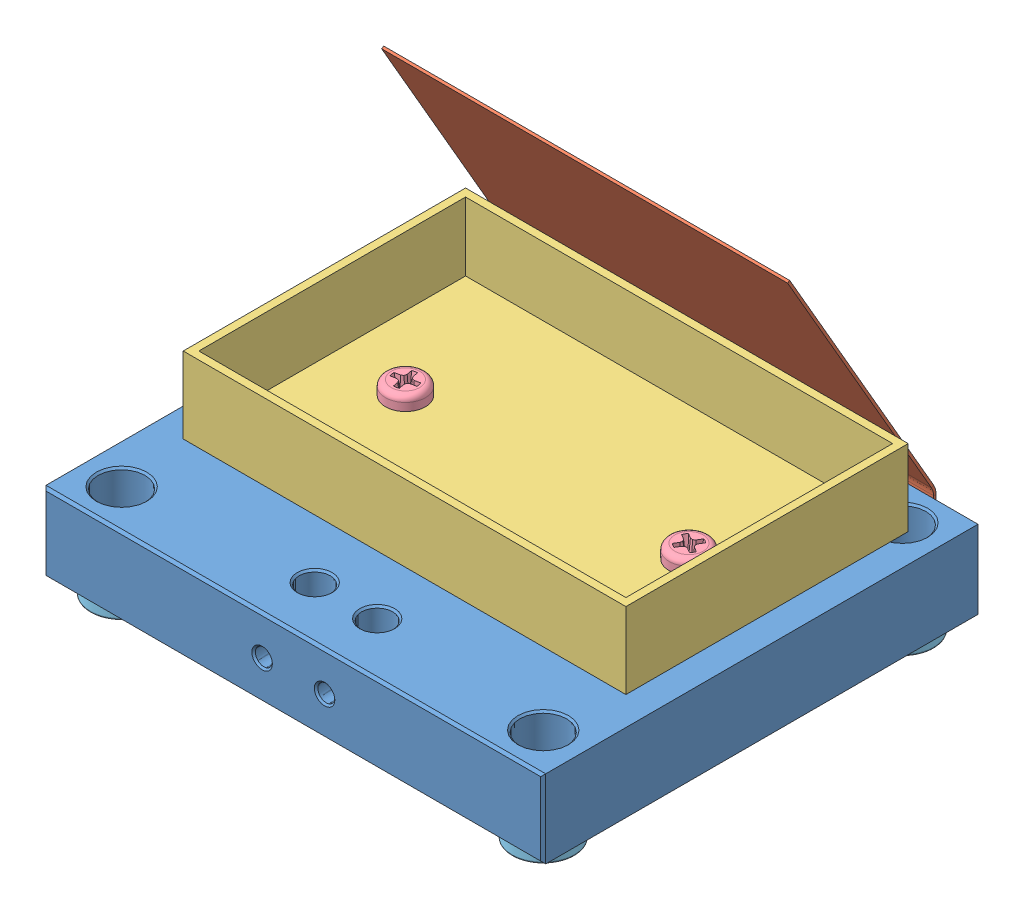
SolidWorks assembly Base_assy, configuration Default. Lengths in mm.
Overall size (101.6 71.58 93.29).
11 component instances, 6 part files, 38 mates.
Components (placement in the parent):
- Base-1: Base [Default] at (101.6 22.2369 0) x (1 0 0) z (0 -1 0) size (101.6 88.9 15.88)
- Plate-1: Plate [Default] at (92.075 22.2369 -0.508) x (0 1 0) z (1 0 0) size (68.4 30.2 82.55)
- 1155_battery_holder-1: 1155_battery_holder [Default] at (95.8 22.2369 8.89) x (0 0 1) z (-1 0 0) size (57.4 15.49 90)
- 8_32_500_nylon_93135A353-1: 8_32_500_nylon_93135A353 [93135A353] at (79.925 23.8244 37.592) x (0.857399 0 0.514652) z (0 1 0) size (8.13 8.13 15.77)
- 8_32_500_nylon_93135A353-2: 8_32_500_nylon_93135A353 [93135A353] at (22.2797 23.8244 37.592) x (0.982082 0 -0.188455) z (0 1 0) size (8.13 8.13 15.77)
- 9309K62_Tight-Grip Push-In Bumpers-1: 9309K62_Tight-Grip Push-In Bumpers [9309K62] at (93.6625 6.3619 7.9375) x (-1 0 0) z (0 0 1) size (12.7 12.7 12.7)
- 9309K62_Tight-Grip Push-In Bumpers-2: 9309K62_Tight-Grip Push-In Bumpers [9309K62] at (93.6625 6.3619 80.9625) x (-1 0 0) z (0 0 1) size (12.7 12.7 12.7)
- 9309K62_Tight-Grip Push-In Bumpers-3: 9309K62_Tight-Grip Push-In Bumpers [9309K62] at (7.9375 6.3619 80.9625) x (-1 0 0) z (0 0 1) size (12.7 12.7 12.7)
- 9309K62_Tight-Grip Push-In Bumpers-4: 9309K62_Tight-Grip Push-In Bumpers [9309K62] at (7.9375 6.3619 7.9375) x (-1 0 0) z (0 0 1) size (12.7 12.7 12.7)
- 90081A291_Zinc-Plated Steel Screw Nails-1: 90081A291_Zinc-Plated Steel Screw Nails [90081A291] at (76.2 14.2994 3.8989) x (0 0 1) z (-1 0 0) size (16.59 10.36 10.36)
- 90081A291_Zinc-Plated Steel Screw Nails-2: 90081A291_Zinc-Plated Steel Screw Nails [90081A291] at (25.4 14.2994 3.8989) x (0 0 1) z (-0.987351 -0.158553 0) size (16.59 10.36 10.36)
Mates (geometry in assembly coordinates):
- Concentric41: concentric: cylinder of ? through (17.4625 25.6067 6.35) axis (0 -1 0) radius 4.064; cylinder of Base-1 through (17.4625 9.5369 6.35) axis (0 -1 0) radius 1.7272
- Concentric44: concentric: cylinder of Base-1 through (84.1375 9.5369 6.35) axis (0 -1 0) radius 1.7272; cylinder of ? through (84.1375 27.5709 6.35) axis (0 -1 0) radius 4.064
- Coincident59: coincident: plane of ? through (84.1375 24.7769 6.35) normal (0 1 0); plane of ? through (84.1375 24.7769 6.35) normal (0 -1 0)
- Coincident61: coincident: plane of ? through (17.4625 24.7769 6.35) normal (0 -1 0); plane of ? through (17.4625 24.7769 6.35) normal (0 1 0)
- Width2: width anti-aligned: plane of Plate-1 through (92.075 22.2369 0) normal (1 0 0); plane of Base-1 through (9.525 22.2369 0) normal (-1 0 0); plane of Plate-1 through (0 6.3619 0) normal (-1 0 0); plane of Base-1 through (101.6 6.3619 0) normal (1 0 0)
- Distance2: distance = 8.89 mm aligned: plane of Base-1 through (101.6 6.3619 0) normal (0 0 -1); plane of 1155_battery_holder-1 through (95.8 23.8244 8.89) normal (0 0 -1)
- Width3: width anti-aligned: plane of Base-1 through (0 6.3619 0) normal (-1 0 0); plane of 1155_battery_holder-1 through (101.6 6.3619 0) normal (1 0 0); plane of Base-1 through (95.8 23.8244 8.89) normal (1 0 0); plane of 1155_battery_holder-1 through (5.8 23.8244 8.89) normal (-1 0 0)
- Coincident65: coincident anti-aligned: plane of Base-1 through (101.6 22.2369 0) normal (0 1 0); plane of ? through (22.2797 22.2369 36.6395) normal (0 -1 0)
- Coincident66: coincident anti-aligned: plane of 1155_battery_holder-1 through (95.8 23.8244 8.89) normal (0 1 0); plane of 8_32_500_nylon_93135A353-1 through (79.925 23.8244 37.592) normal (0 -1 0)
- Concentric55: concentric anti-aligned: cylinder of 1155_battery_holder-1 through (79.925 23.8244 37.592) axis (0 1 0) radius 2.2479; cylinder of 8_32_500_nylon_93135A353-1 through (79.925 26.6184 37.592) axis (0 -1 0) radius 4.064
- Coincident67: coincident anti-aligned: plane of 1155_battery_holder-1 through (95.8 23.8244 8.89) normal (0 1 0); plane of 8_32_500_nylon_93135A353-2 through (22.2797 23.8244 37.592) normal (0 -1 0)
- Concentric56: concentric anti-aligned: cylinder of 1155_battery_holder-1 through (22.2797 23.8244 37.592) axis (0 1 0) radius 2.2479; cylinder of 8_32_500_nylon_93135A353-2 through (22.2797 26.6184 37.592) axis (0 -1 0) radius 4.064
- Concentric57: concentric: cylinder of ? through (17.4625 27.5709 6.35) axis (0 -1 0) radius 4.064; circle of ?
- Concentric58: concentric: cylinder of ? through (17.4625 27.5709 6.35) axis (0 -1 0) radius 4.064; circle of ?
- Coincident69: coincident: plane of ? through (17.4625 23.7609 6.35) normal (0 1 0); plane of ? through (17.4625 23.7609 6.35) normal (0 -1 0)
- Concentric59: concentric: cylinder of ? through (84.1375 27.5709 6.35) axis (0 -1 0) radius 4.064; circle of ?
- Concentric60: concentric: cylinder of ? through (84.1375 27.5709 6.35) axis (0 -1 0) radius 4.064; circle of ?
- Coincident71: coincident: plane of ? through (84.1375 23.7609 6.35) normal (0 1 0); plane of ? through (84.1375 23.7609 6.35) normal (0 -1 0)
- Coincident72: coincident anti-aligned: plane of Base-1 through (101.6 22.2369 0) normal (0 1 0); plane of 1155_battery_holder-1 through (95.8 22.2369 8.89) normal (0 -1 0)
- Coincident73: coincident anti-aligned: plane of Base-1 through (101.6 6.3619 0) normal (0 0 -1); plane of Plate-1 through (92.075 22.2369 0) normal (0 0 1)
- Concentric61: concentric aligned: cylinder of Base-1 through (76.2 14.2994 0) axis (0 0 -1) radius 2.4892; cylinder of Plate-1 through (76.2 14.2994 -0.508) axis (0 0 -1) radius 3.175
- Concentric62: concentric anti-aligned: cylinder of Base-1 through (76.2 14.2994 0) axis (0 0 -1) radius 2.4892; cylinder of ? through (76.2 15.8869 -3.302) axis (0 0 1) radius 4.064
- Coincident75: coincident anti-aligned: plane of Base-1 through (101.6 6.3619 0) normal (0 -1 0); plane of 9309K62_Tight-Grip Push-In Bumpers-1 through (87.3125 6.3619 7.9375) normal (0 1 0)
- Concentric65: concentric aligned: cylinder of Base-1 through (93.6625 22.2369 7.9375) axis (0 -1 0) radius 3.175; cylinder of 9309K62_Tight-Grip Push-In Bumpers-1 through (93.6625 3.1869 7.9375) axis (0 -1 0) radius 3.175
- Parallel4: parallel aligned: plane of 9309K62_Tight-Grip Push-In Bumpers-1 through (93.6625 6.3619 7.9375) normal (0 0 1)
- Coincident77: coincident anti-aligned: plane of Base-1 through (101.6 6.3619 0) normal (0 -1 0); plane of 9309K62_Tight-Grip Push-In Bumpers-2 through (87.3125 6.3619 80.9625) normal (0 1 0)
- Parallel5: parallel aligned: plane of 9309K62_Tight-Grip Push-In Bumpers-2 through (93.6625 6.3619 80.9625) normal (0 0 1)
- Concentric66: concentric anti-aligned: cylinder of Base-1 through (93.6625 22.2369 80.9625) axis (0 1 0) radius 4.7625; cylinder of 9309K62_Tight-Grip Push-In Bumpers-2 through (93.6625 3.1869 80.9625) axis (0 -1 0) radius 3.175
- Coincident78: coincident anti-aligned: plane of Base-1 through (101.6 6.3619 0) normal (0 -1 0); plane of 9309K62_Tight-Grip Push-In Bumpers-3 through (1.5875 6.3619 80.9625) normal (0 1 0)
- Parallel6: parallel aligned: plane of 9309K62_Tight-Grip Push-In Bumpers-3 through (7.9375 6.3619 80.9625) normal (0 0 1)
- Concentric67: concentric anti-aligned: cylinder of Base-1 through (7.9375 22.2369 80.9625) axis (0 1 0) radius 4.7625; cylinder of 9309K62_Tight-Grip Push-In Bumpers-3 through (7.9375 3.1869 80.9625) axis (0 -1 0) radius 3.175
- Coincident79: coincident anti-aligned: plane of Base-1 through (101.6 6.3619 0) normal (0 -1 0); plane of 9309K62_Tight-Grip Push-In Bumpers-4 through (1.5875 6.3619 7.9375) normal (0 1 0)
- Parallel7: parallel aligned: plane of 9309K62_Tight-Grip Push-In Bumpers-4 through (7.9375 6.3619 7.9375) normal (0 0 1)
- Concentric68: concentric anti-aligned: cylinder of Base-1 through (7.9375 22.2369 7.9375) axis (0 1 0) radius 4.7625; cylinder of 9309K62_Tight-Grip Push-In Bumpers-4 through (7.9375 3.1869 7.9375) axis (0 -1 0) radius 3.175
- Concentric69: concentric anti-aligned: cylinder of Base-1 through (76.2 14.2994 0) axis (0 0 -1) radius 2.4892; cylinder of 90081A291_Zinc-Plated Steel Screw Nails-1 through (76.2 14.2994 12.192) axis (0 0 1) radius 2.2479
- Coincident80: coincident anti-aligned: plane of Plate-1 through (92.075 22.2369 -0.508) normal (0 0 -1); plane of 90081A291_Zinc-Plated Steel Screw Nails-1 through (76.2 16.9918 -0.508) normal (0 0 1)
- Coincident81: coincident anti-aligned: plane of Plate-1 through (92.075 22.2369 -0.508) normal (0 0 -1); plane of 90081A291_Zinc-Plated Steel Screw Nails-2 through (24.9731 16.9578 -0.508) normal (0 0 1)
- Concentric70: concentric anti-aligned: cylinder of Base-1 through (25.4 14.2994 0) axis (0 0 -1) radius 2.4892; cylinder of 90081A291_Zinc-Plated Steel Screw Nails-2 through (25.4 14.2994 12.192) axis (0 0 1) radius 2.2479
